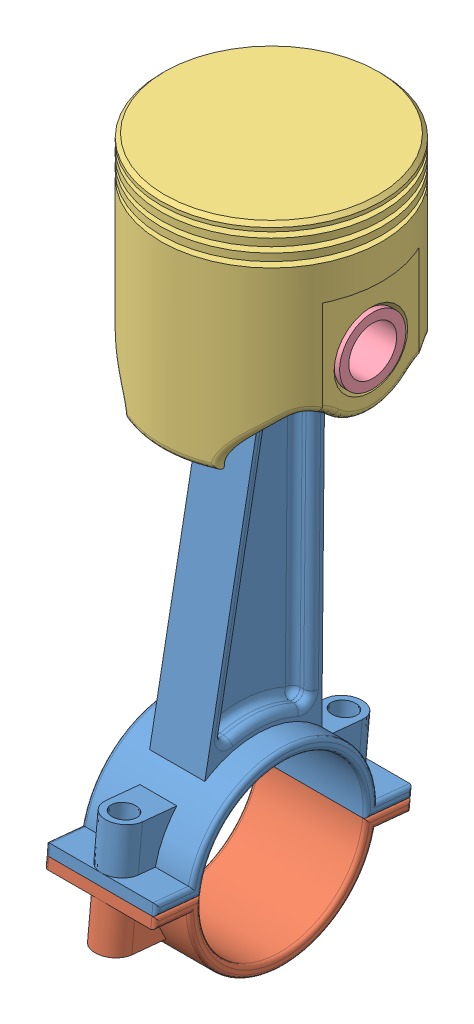
SolidWorks assembly Piston Sub Assembly, configuration Default. Lengths in mm.
Overall size (60 186 84.96).
4 component instances, 4 part files, 8 mates.
Components (placement in the parent):
- Connecting Rod-1: Connecting Rod [Default] at (0 -37.4052 0) x (0 0.096525 0.995331) z (-1 0 0) size (70 132.9 30)
- Connecting Rod Lock-1: Connecting Rod Lock [Default] at (0 -157.243 11.6216) x (0 -0.096525 -0.995331) z (1 0 0) size (70 25.5 30)
- Piston-1: Piston [Default] at origin size (60 60.17 60)
- Piston Pin-1: Piston Pin [Default] at (0 -37.4052 0) size (55 18 18)
Mates (geometry in assembly coordinates):
- Concentric1: concentric anti-aligned: cylinder of Connecting Rod-1 through (-10 -37.4052 0) axis (1 0 0) radius 9; cylinder of Piston-1 through (30 -37.4052 0) axis (-1 0 0) radius 9
- Width1: width aligned: plane of Connecting Rod-1 through (-10 -37.4052 0) normal (-1 0 0); plane of Connecting Rod-1 through (10 -37.4052 0) normal (1 0 0); plane of Piston-1 through (10 -38 0) normal (-1 0 0); plane of Piston-1 through (-10 -38 0) normal (1 0 0)
- Concentric2: concentric anti-aligned: cylinder of Piston-1 through (-30 -37.4052 0) axis (1 0 0) radius 9; cylinder of Piston Pin-1 through (27.5 -37.4052 0) axis (-1 0 0) radius 9
- Width2: width anti-aligned: plane of Piston Pin-1 through (27.5 -37.4052 0) normal (1 0 0); plane of Piston Pin-1 through (-27.5 -37.4052 0) normal (-1 0 0); plane of Piston-1 through (-27 0 0) normal (-1 0 0); plane of Piston-1 through (27 0 0) normal (1 0 0)
- Coincident1: coordinate: point of Piston-1
- Coincident2: coincident anti-aligned: plane of Connecting Rod-1 through (-15 -157.243 11.6216) normal (0 -0.995331 0.096525); plane of Connecting Rod Lock-1 through (15 -159.4148 -10.7734) normal (0 0.995331 -0.096525)
- Concentric3: concentric anti-aligned: cylinder of Connecting Rod-1 through (0 -160.1387 -18.2383) axis (0 0.995331 -0.096525) radius 3.25; cylinder of Connecting Rod Lock-1 through (0 -160.1387 -18.2383) axis (0 -0.995331 0.096525) radius 3.25
- Concentric4: concentric anti-aligned: cylinder of Connecting Rod-1 through (0 -154.3472 41.4815) axis (0 0.995331 -0.096525) radius 3.25; cylinder of Connecting Rod Lock-1 through (0 -154.3472 41.4815) axis (0 -0.995331 0.096525) radius 3.25
